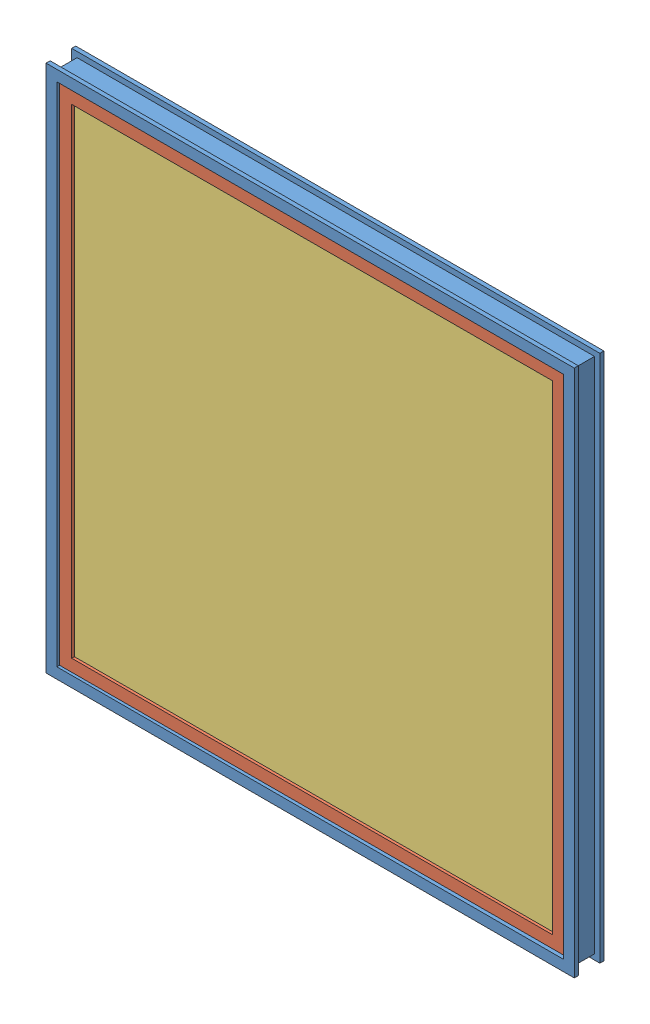
SolidWorks assembly 2020 WINDOW, configuration Default. Lengths in mm.
Overall size (622.3 622.3 34.92).
4 component instances, 3 part files, 8 mates.
Components (placement in the parent):
- SQUARE WINDOW MOLD-1: SQUARE WINDOW MOLD [Default] at (259.1951 73.7438 426.9234) size (622.3 622.3 34.92)
- INSERT WINDOW MOLD-1: INSERT WINDOW MOLD [Default] at (259.1754 81.6813 432.6799) x (0.999998 0 -0.001999) z (0.001999 0 0.999998) size (593.72 593.72 19.05)
- 2020 GLASS-2: 2020 GLASS [Default] at (259.9565 377.75 426.3283) x (0.001999 0 0.999998) z (-0.999998 0 0.001999) size (4.76 579.44 579.44)
- 2020 GLASS-3: 2020 GLASS [Default] at (258.3944 377.75 439.0315) x (-0.001999 0 -0.999998) z (0.999998 0 -0.001999) size (4.76 579.44 579.44)
Mates (geometry in assembly coordinates):
- Coincident4: coincident anti-aligned: line of SQUARE WINDOW MOLD-1 through (-37.6674 80.0938 442.7984) axis (0 1 0); line of INSERT WINDOW MOLD-1 through (-37.6674 675.4063 442.7984) axis (0 -1 0)
- Distance1: distance = 1.5875 mm anti-aligned: plane of INSERT WINDOW MOLD-1 through (-37.6674 81.6813 442.7984) normal (0 -1 0); plane of SQUARE WINDOW MOLD-1 through (571.0801 80.0938 444.3859) normal (0 1 0)
- Coincident9: coincident anti-aligned: plane of INSERT WINDOW MOLD-1 through (541.7372 81.6813 425.765) normal (0.001999 0 0.999998); plane of 2020 GLASS-2 through (259.9565 377.75 426.3283) normal (-0.001999 0 -0.999998)
- Distance3: distance = 1.5875 mm anti-aligned: plane of 2020 GLASS-2 through (549.6842 88.0313 430.5116) normal (0.999998 0 -0.001999); plane of INSERT WINDOW MOLD-1 through (551.2622 81.6813 425.7459) normal (-0.999998 0 0.001999)
- Distance4: distance = 1.5875 mm anti-aligned: plane of 2020 GLASS-2 through (-29.7522 88.0313 431.67) normal (0 -1 0); plane of INSERT WINDOW MOLD-1 through (-37.6992 86.4438 426.9234) normal (0 1 0)
- Coincident12: coincident anti-aligned: plane of INSERT WINDOW MOLD-1 through (551.2875 81.6813 438.4459) normal (-0.001999 0 -0.999998); plane of 2020 GLASS-3 through (258.3944 377.75 439.0315) normal (0.001999 0 0.999998)
- Distance5: distance = 1.5875 mm anti-aligned: plane of 2020 GLASS-3 through (-31.3333 88.0313 434.8482) normal (-0.999998 0 0.001999); plane of INSERT WINDOW MOLD-1 through (-32.9367 675.4063 426.9139) normal (0.999998 0 -0.001999)
- Distance6: distance = 1.5875 mm anti-aligned: plane of INSERT WINDOW MOLD-1 through (-37.6992 86.4438 426.9234) normal (0 1 0); plane of 2020 GLASS-3 through (548.103 88.0313 433.6897) normal (0 -1 0)
